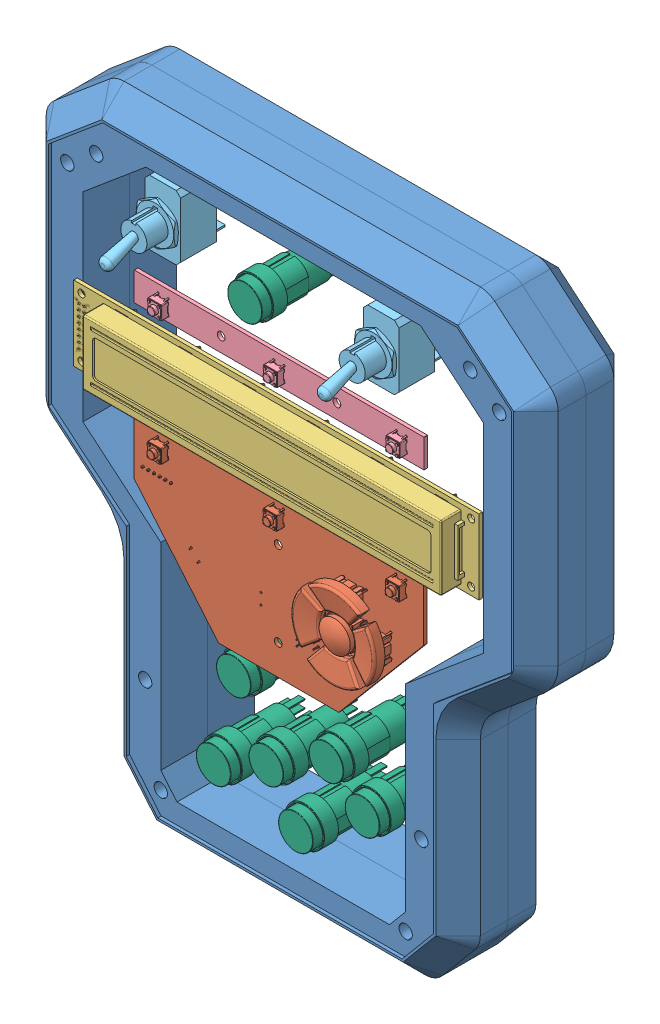
SolidWorks assembly Montagem003, configuration Valor predeterminado. Lengths in mm.
Overall size (230 298 72.34).
16 component instances, 7 part files, 14 mates.
Components (placement in the parent):
- 3 - TEC02 - Moldura-1: 3 - TEC02 - Moldura [Valor predeterminado] at (-42.8561 -137.5176 288.75) size (230 280 22.5)
- 3 - TEC02 - Moldura-2: 3 - TEC02 - Moldura [Valor predeterminado] at (-42.8561 -137.5176 288.75) x (-1 0 0) z (0 0 -1) size (230 280 22.5)
- 3 - TEC03 - Placa Superior-1: 3 - TEC03 - Placa Superior [Valor predeterminado] at (-42.8561 30.7308 267.75) x (-1 0 0) z (0 0 -1) size (208 278 1.5) (hidden)
- 3 - TEC03 - Placa Superior-2: 3 - TEC03 - Placa Superior [Valor predeterminado] at (-42.8561 10.7308 309.75) size (208 278 1.5) (hidden)
- PCB_IHM_Reduzida-1: PCB_IHM_Reduzida [Valor predeterminado] at (10.8777 30.2796 312.8414) size (130 70 21.73)
- LCD Display 4002-1: LCD Display 4002 [Valor predeterminado] at (-42.8561 48.6812 308.3036) size (182 33.5 13.65)
- Teclado_Superior_Reduzido-1: Teclado_Superior_Reduzido [Valor predeterminado] at (11.0421 72.8275 312.8414) size (130.25 12.75 8.5)
- BCV3 112 103 - Controle chave geral-1: BCV3 112 103 - Controle chave geral [Default] at (-96.9463 105.684 301.75) size (17 29 51.5)
- BCV3 112 102 - Controle botão-1: BCV3 112 102 - Controle botão [Valor predeterminado] at (-38.6953 -71.2693 311.25) x (1 0 0) z (0 -1 0) size (17.7 39.7 17.7)
- BCV3 112 102 - Controle botão-3: BCV3 112 102 - Controle botão [Valor predeterminado] at (-12.2494 -57.0028 310.7) x (1 0 0) z (0 -1 0) size (17.7 39.7 17.7)
- BCV3 112 102 - Controle botão-4: BCV3 112 102 - Controle botão [Valor predeterminado] at (-66.3396 -57.0028 298.2) x (1 0 0) z (0 -1 0) size (17.7 39.7 17.7)
- BCV3 112 102 - Controle botão-5: BCV3 112 102 - Controle botão [Valor predeterminado] at (-38.4623 -103.6036 298.2) x (1 0 0) z (0 -1 0) size (17.7 39.7 17.7)
- BCV3 112 102 - Controle botão-6: BCV3 112 102 - Controle botão [Valor predeterminado] at (-12.4535 -86.5612 294.2578) x (1 0 0) z (0 -1 0) size (17.7 39.7 17.7)
- BCV3 112 102 - Controle botão-7: BCV3 112 102 - Controle botão [Valor predeterminado] at (-65.9235 -86.5444 307.65) x (1 0 0) z (0 -1 0) size (17.7 39.7 17.7)
- BCV3 112 103 - Controle chave geral-4: BCV3 112 103 - Controle chave geral [Default] at (1.6393 104.7383 302.2945) size (17 29 51.5)
- BCV3 112 102 - Controle botão-8: BCV3 112 102 - Controle botão [Valor predeterminado] at (-47.8002 104.4395 311.6979) x (1 0 0) z (0 -1 0) size (17.7 39.7 17.7)
Mates (geometry in assembly coordinates):
- Coincidente1: coincident anti-aligned: plane of 3 - TEC02 - Moldura-1 through (-42.8561 -137.5176 288.75) normal (0 0 -1); plane of 3 - TEC02 - Moldura-2 through (-42.8561 -137.5176 288.75) normal (0 0 1)
- Coincidente2: coincident aligned: plane of 3 - TEC02 - Moldura-1 through (-157.8561 -137.5176 311.25) normal (-1 0 0); plane of 3 - TEC02 - Moldura-2 through (-157.8561 -137.5176 266.25) normal (-1 0 0)
- Coincidente3: coincident aligned: plane of 3 - TEC02 - Moldura-1 through (-42.8561 142.4824 311.25) normal (0 1 0); plane of 3 - TEC02 - Moldura-2 through (-42.8561 142.4824 266.25) normal (0 1 0)
- Coincidente4: coincident anti-aligned: plane of 3 - TEC02 - Moldura-1 through (-42.8561 -137.5176 309.75) normal (0 0 1); plane of 3 - TEC03 - Placa Superior-2 through (-42.8561 10.7308 309.75) normal (0 0 -1)
- Coincidente5: coincident anti-aligned: plane of 3 - TEC02 - Moldura-1 through (-146.8561 111.0386 309.75) normal (1 0 0); plane of 3 - TEC03 - Placa Superior-2 through (-146.8561 111.0386 311.25) normal (-1 0 0)
- Coincidente6: coincident anti-aligned: plane of 3 - TEC02 - Moldura-1 through (-122.4921 131.4824 309.75) normal (0 -1 0); plane of 3 - TEC03 - Placa Superior-2 through (-122.4921 131.4824 311.25) normal (0 1 0)
- Coincidente7: coincident anti-aligned: plane of 3 - TEC02 - Moldura-2 through (-42.8561 -137.5176 267.75) normal (0 0 -1); plane of 3 - TEC03 - Placa Superior-1 through (-42.8561 30.7308 267.75) normal (0 0 1)
- Coincidente8: coincident anti-aligned: plane of 3 - TEC02 - Moldura-2 through (61.1439 111.0386 267.75) normal (-1 0 0); plane of 3 - TEC03 - Placa Superior-1 through (61.1439 131.0386 266.25) normal (1 0 0)
- Coincidente9: coincident anti-aligned: plane of 3 - TEC02 - Moldura-2 through (12.0145 -126.5176 267.75) normal (0 1 0); plane of 3 - TEC03 - Placa Superior-1 through (12.0145 -126.5176 266.25) normal (0 -1 0)
- Coincidente10: coincident anti-aligned: plane of 3 - TEC03 - Placa Superior-2 through (-42.8561 10.7308 311.25) normal (0 0 1); plane of BCV3 112 102 - Controle botão-1 through (-38.6953 -71.2693 311.25) normal (0 0 -1)
- Coincidente11: coincident anti-aligned: plane of 3 - TEC03 - Placa Superior-2 through (-42.8561 10.7308 311.25) normal (0 0 1); plane of PCB_IHM_Reduzida-1 through (-68.7723 -43.2394 311.25) normal (0 0 -1)
- Coincidente12: coincident anti-aligned: plane of 3 - TEC03 - Placa Superior-2 through (-42.8561 10.7308 311.25) normal (0 0 1); plane of LCD Display 4002-1 through (-42.8561 48.6812 311.25) normal (0 0 -1)
- Coincidente13: coincident anti-aligned: plane of 3 - TEC03 - Placa Superior-2 through (-42.8561 10.7308 311.25) normal (0 0 1); plane of Teclado_Superior_Reduzido-1 through (-106.6079 70.1815 311.25) normal (0 0 -1)
- Coincidente14: coincident anti-aligned: plane of 3 - TEC03 - Placa Superior-2 through (-42.8561 10.7308 311.25) normal (0 0 1); plane of BCV3 112 103 - Controle chave geral-1 through (-96.9463 115.4989 311.25) normal (0 0 -1)
